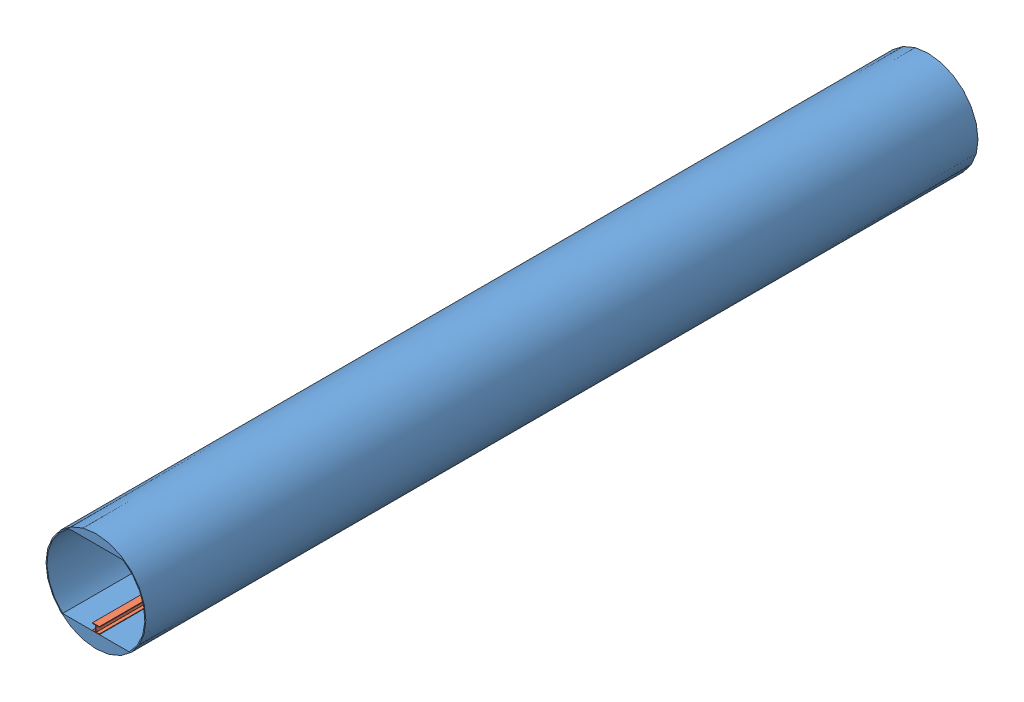
SolidWorks assembly test_track, configuration Default. Lengths in mm.
Overall size (1828.8 1828.8 15240).
2 component instances, 2 part files, 3 mates.
Components (placement in the parent):
- tunnel-1: tunnel [Default] at (2830.8665 4983.259 8849.2099) size (1828.8 1828.8 15240)
- rail_v2-1: rail_v2 [Default] at (2830.8665 4389.2521 4277.2099) size (127 127 15240)
Mates (geometry in assembly coordinates):
- Rail on Tube Floor: coincident: plane of tunnel-1 through (2221.2665 4325.7521 -3342.7901) normal (0 1 0); plane of rail_v2-1 through (2892.8425 4325.7521 11583.197) normal (0 -1 0)
- Rail Along Tube Centerline: coincident: plane of tunnel-1 through (2830.8665 4983.259 8849.2099) normal (1 0 0); plane of rail_v2-1 through (2830.8665 4389.2521 3963.197) normal (1 0 0)
- Rail Flush with Tube Front: coincident aligned: plane of tunnel-1 through (2830.8665 4983.259 11897.2099) normal (0 0 1); plane of rail_v2-1 through (2768.8905 4327.2761 11897.2099) normal (0 0 1)
